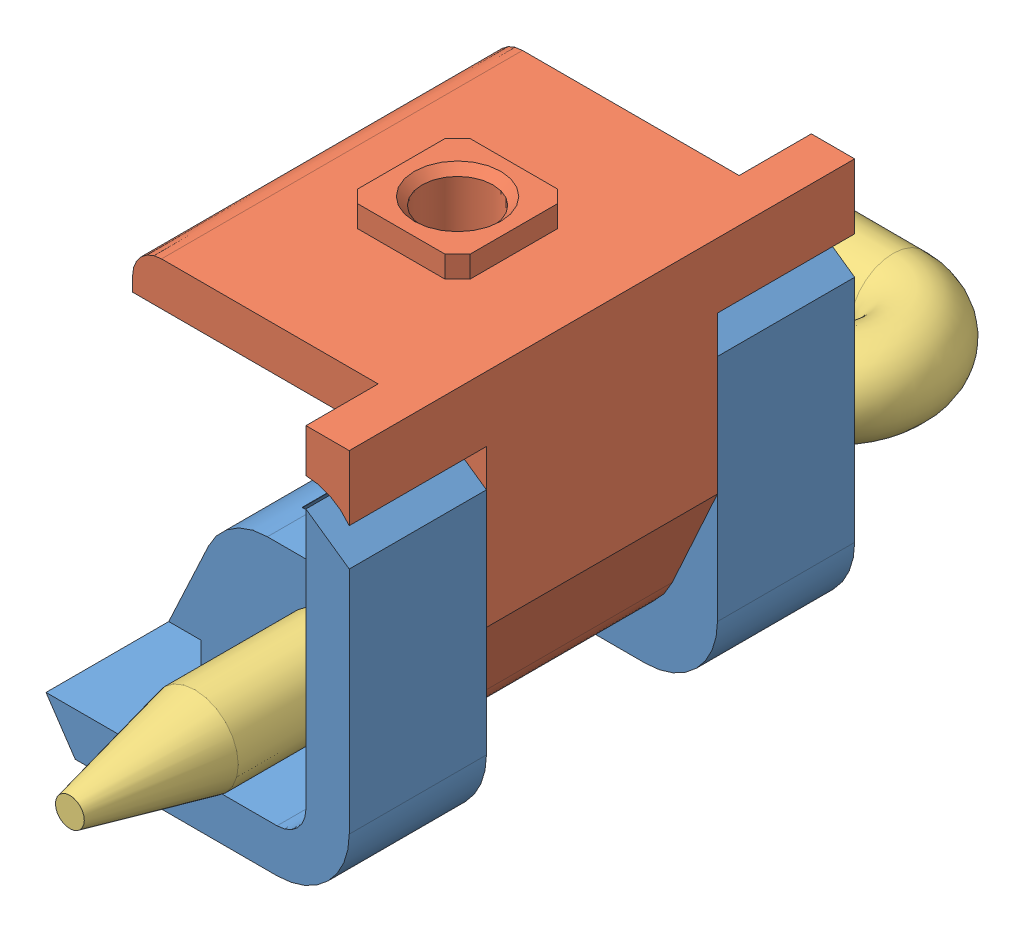
SolidWorks assembly dirak_85-7-2245, configuration Défaut. Lengths in mm.
Overall size (21 29.5 62).
3 component instances, 3 part files, 4 mates.
Components (placement in the parent):
- dirak_212-9712_d2iej04vlz8i2qitidpe4nzpu_1-1: dirak_212-9712_d2iej04vlz8i2qitidpe4nzpu_1 [Défaut] at (-27.6553 -20.5106 36.1002) size (21 23 35)
- dirak_212-9712_d2iej04vlz8i2qitidpe4nzpu_2-1: dirak_212-9712_d2iej04vlz8i2qitidpe4nzpu_2 [Défaut] at (-27.6553 -20.5106 36.1002) size (20 26.85 35)
- dirak_212-9712_d2iej04vlz8i2qitidpe4nzpu_3-1: dirak_212-9712_d2iej04vlz8i2qitidpe4nzpu_3 [Défaut] at (-27.6553 -63.5106 26.9475) x (1 0 0) z (0 0 -1) size (14 6.01 62)
Mates (geometry in assembly coordinates):
- Coaxiale1: concentric aligned: cylinder of dirak_212-9712_d2iej04vlz8i2qitidpe4nzpu_2-1 through (-25.6553 -42.0106 36.1002) axis (0 0 1) radius 3; cylinder of dirak_212-9712_d2iej04vlz8i2qitidpe4nzpu_3-1 through (-25.6553 -42.0106 25.6475) axis (0 0 1) radius 3
- Coaxiale2: concentric aligned: cylinder of dirak_212-9712_d2iej04vlz8i2qitidpe4nzpu_2-1 through (-25.6553 -42.0106 36.1002) axis (0 0 1) radius 3; cylinder of dirak_212-9712_d2iej04vlz8i2qitidpe4nzpu_3-1 through (-25.6553 -42.0106 25.6475) axis (0 0 1) radius 3
- Coaxiale3: concentric aligned: cylinder of dirak_212-9712_d2iej04vlz8i2qitidpe4nzpu_1-1 through (-25.6553 -42.0106 36.1002) axis (0 0 1) radius 3; cylinder of dirak_212-9712_d2iej04vlz8i2qitidpe4nzpu_3-1 through (-25.6553 -42.0106 25.6475) axis (0 0 1) radius 3
- Coïncidente1: coincident anti-aligned: plane of dirak_212-9712_d2iej04vlz8i2qitidpe4nzpu_1-1 through (-24.0196 -40.2353 28.1002) normal (0 0 1); plane of dirak_212-9712_d2iej04vlz8i2qitidpe4nzpu_2-1 through (-24.7071 -33.8302 28.1002) normal (0 0 -1)
